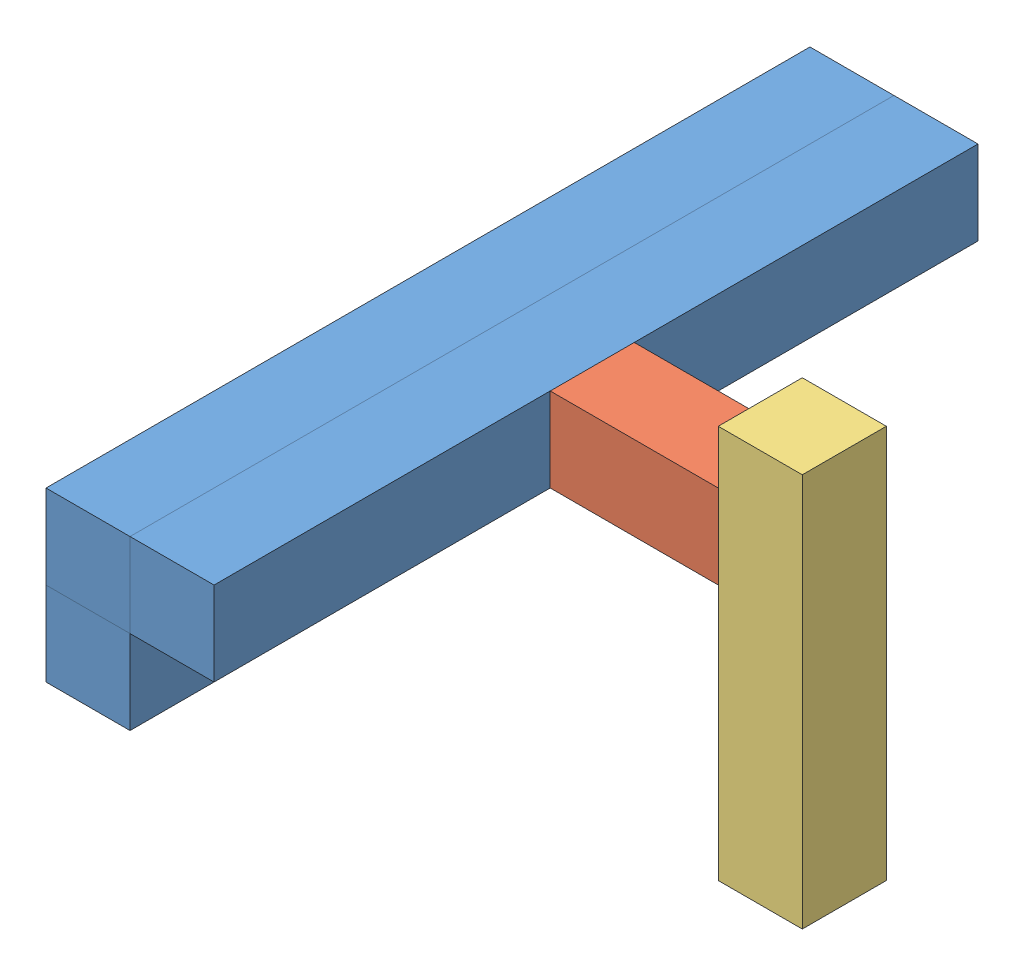
SolidWorks assembly porte_message_violet, configuration Default. Lengths in mm.
Overall size (110 103 200).
5 component instances, 3 part files, 12 mates.
Components (placement in the parent):
- linteau_22x22_L200_violet-1: linteau_22x22_L200_violet [Default] at (-32.4883 2.9464 101.8641) size (22 22 200)
- linteau_22x22_L200_violet-2: linteau_22x22_L200_violet [Default] at (-10.4883 2.9464 101.8641) size (22 22 200)
- linteau_22x22_L44_violet-1: linteau_22x22_L44_violet [Default] at (11.5117 2.9464 -8.1359) x (0 0 1) z (-1 0 0) size (22 22 44)
- linteau_22x22_L103_violet-1: linteau_22x22_L103_violet [Default] at (55.5117 -64.0536 -8.1359) x (1 0 0) z (0 -1 0) size (22 22 103)
- linteau_22x22_L200_violet-3: linteau_22x22_L200_violet [Default] at (-32.4883 -19.0536 101.8641) size (22 22 200)
Mates (geometry in assembly coordinates):
- Coïncidente1: coincident anti-aligned: plane of linteau_22x22_L200_violet-1 through (-10.4883 2.9464 -98.1359) normal (1 0 0); plane of linteau_22x22_L200_violet-2 through (-10.4883 2.9464 -98.1359) normal (-1 0 0)
- Coïncidente2: coincident aligned: plane of linteau_22x22_L200_violet-1 through (-32.4883 2.9464 -98.1359) normal (0 -1 0); plane of linteau_22x22_L200_violet-2 through (-10.4883 2.9464 -98.1359) normal (0 -1 0)
- Coïncidente3: coincident aligned: plane of linteau_22x22_L200_violet-1 through (-32.4883 24.9464 101.8641) normal (0 0 1); plane of linteau_22x22_L200_violet-2 through (-10.4883 24.9464 101.8641) normal (0 0 1)
- Coïncidente4: coincident anti-aligned: plane of linteau_22x22_L200_violet-2 through (11.5117 2.9464 -98.1359) normal (1 0 0); plane of linteau_22x22_L44_violet-1 through (11.5117 24.9464 -8.1359) normal (-1 0 0)
- Coïncidente5: coincident aligned: plane of linteau_22x22_L200_violet-2 through (-10.4883 24.9464 -98.1359) normal (0 1 0); plane of linteau_22x22_L44_violet-1 through (55.5117 24.9464 -8.1359) normal (0 1 0)
- Distance1: distance = 88 mm aligned: plane of linteau_22x22_L44_violet-1 through (55.5117 2.9464 13.8641) normal (0 0 1); plane of linteau_22x22_L200_violet-2 through (-10.4883 24.9464 101.8641) normal (0 0 1)
- Coïncidente6: coincident anti-aligned: plane of linteau_22x22_L44_violet-1 through (55.5117 24.9464 -8.1359) normal (1 0 0); plane of linteau_22x22_L103_violet-1 through (55.5117 38.9464 -8.1359) normal (-1 0 0)
- Coïncidente7: coincident aligned: plane of linteau_22x22_L103_violet-1 through (55.5117 38.9464 13.8641) normal (0 0 1); plane of linteau_22x22_L44_violet-1 through (55.5117 2.9464 13.8641) normal (0 0 1)
- Distance2: distance = 67 mm aligned: plane of linteau_22x22_L103_violet-1 through (55.5117 -64.0536 13.8641) normal (0 -1 0); plane of linteau_22x22_L200_violet-2 through (-10.4883 2.9464 -98.1359) normal (0 -1 0)
- Coïncidente8: coincident: plane of linteau_22x22_L200_violet-1 through (-32.4883 2.9464 -98.1359) normal (0 -1 0); plane of ? through (-30.1507 2.9464 -98.1359) normal (0 1 0)
- Coïncidente9: coincident: plane of linteau_22x22_L200_violet-1 through (-32.4883 24.9464 101.8641) normal (0 0 1); plane of ? through (-30.1507 2.9464 101.8641) normal (0 0 1)
- Coïncidente10: coincident aligned: plane of linteau_22x22_L200_violet-1 through (-32.4883 2.9464 -98.1359) normal (-1 0 0); plane of ? through (-30.1507 -19.0536 -98.1359) normal (-1 0 0)
